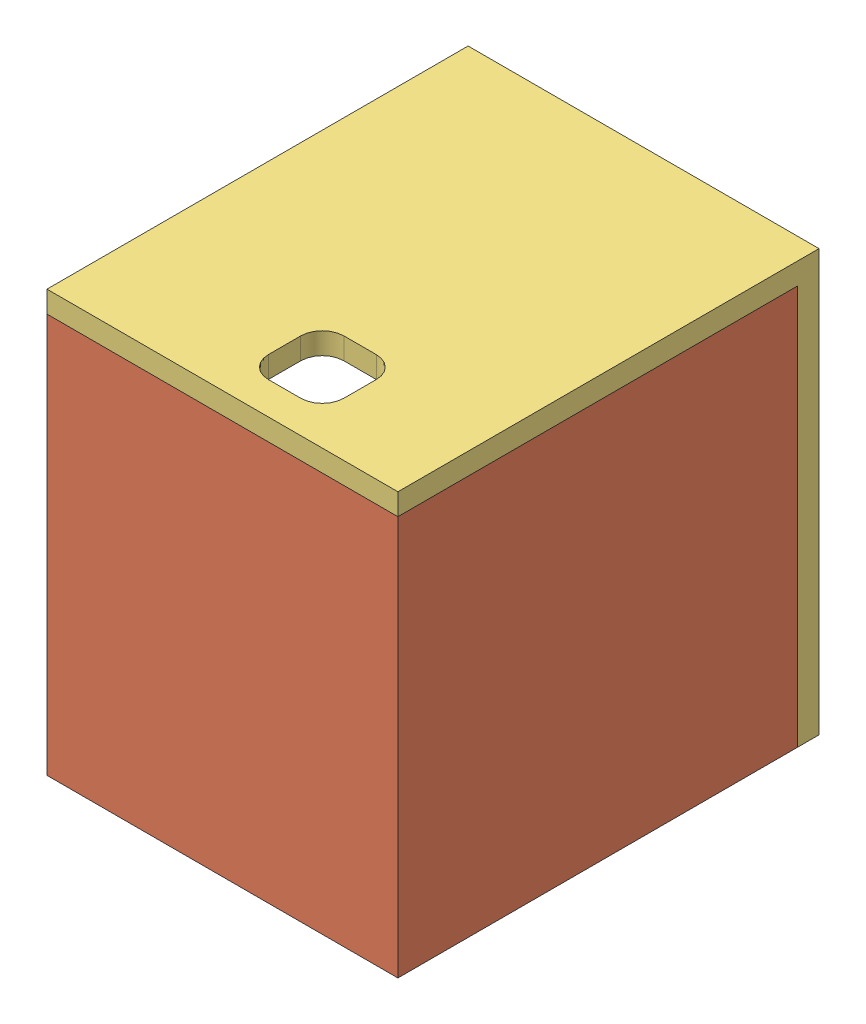
SolidWorks assembly Assem1, configuration Default. Lengths in mm.
Overall size (32.5 39 39).
3 component instances, 3 part files, 7 mates.
Components (placement in the parent):
- disp-part1-1: disp-part1 [Default] at (3.9768 25.9328 30.8677) x (0 -1 0) z (1 0 0) size (35 33 4)
- rf-part1-1: rf-part1 [Default] at (21.9768 24.4328 54.8677) x (-1 0 0) z (0 0 -1) size (32.5 37 37)
- close-part1-1: close-part1 [Default] at (20.2268 45.4328 36.3677) x (-1 0 0) z (0 -1 0) size (32.5 39 39)
Mates (geometry in assembly coordinates):
- Coincident4: coincident aligned: plane of disp-part1-1 through (3.9768 25.9328 30.8677) normal (-1 0 0); plane of rf-part1-1 through (3.9768 8.4328 17.8677) normal (-1 0 0)
- Coincident7: coincident anti-aligned: plane of disp-part1-1 through (7.9768 40.4328 50.8677) normal (0 0 1); plane of rf-part1-1 through (7.9768 8.4328 50.8677) normal (0 0 -1)
- Coincident9: coincident anti-aligned: plane of disp-part1-1 through (3.9768 8.4328 30.8677) normal (0 -1 0); plane of rf-part1-1 through (36.4768 8.4328 17.8677) normal (0 1 0)
- Parallel1: parallel anti-aligned: plane of rf-part1-1 through (36.4768 43.4328 52.8677) normal (0 1 0); plane of close-part1-1 through (20.2268 43.4328 36.3677) normal (0 -1 0)
- Coincident14: coincident aligned: plane of rf-part1-1 through (36.4768 8.4328 52.8677) normal (1 0 0); plane of close-part1-1 through (36.4768 43.4328 54.8677) normal (1 0 0)
- Coincident15: coincident aligned: plane of rf-part1-1 through (21.9768 24.4328 54.8677) normal (0 0 1); plane of close-part1-1 through (36.4768 43.4328 54.8677) normal (0 0 1)
- Coincident16: coincident anti-aligned: plane of rf-part1-1 through (36.4768 43.4328 52.8677) normal (0 1 0); plane of close-part1-1 through (20.2268 43.4328 36.3677) normal (0 -1 0)
